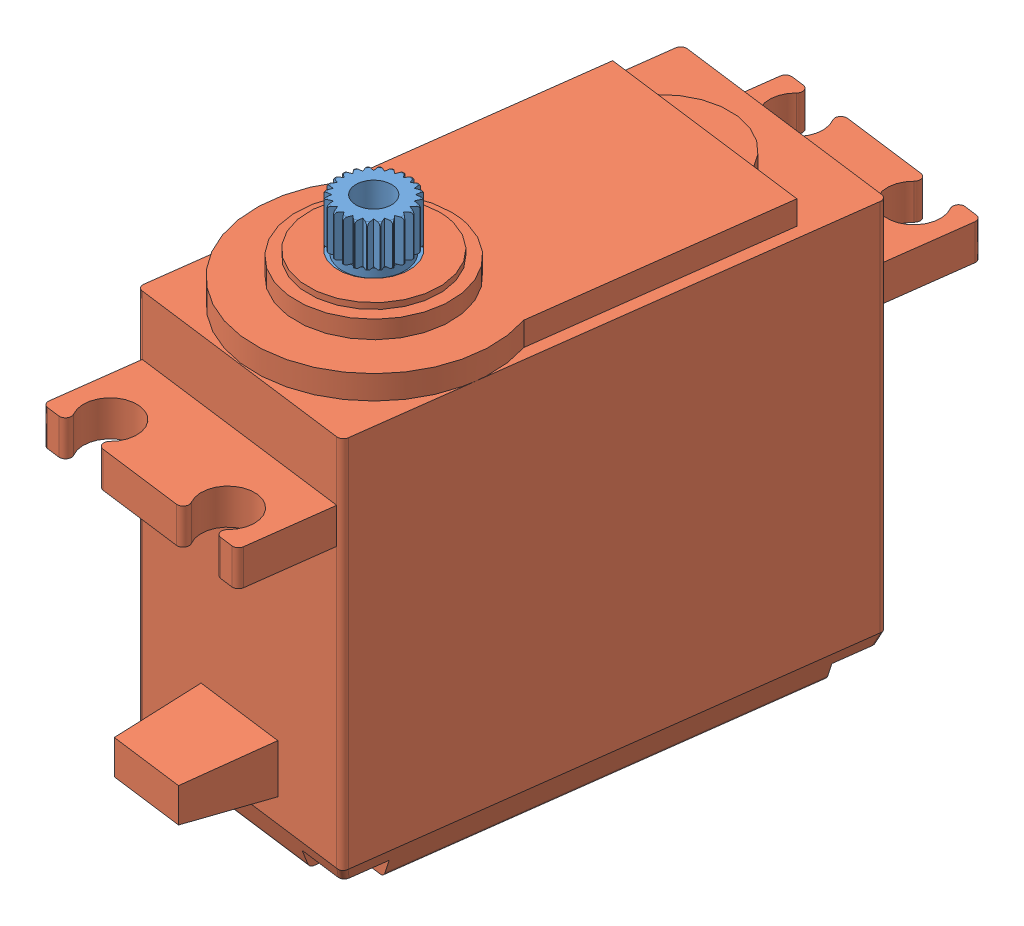
SolidWorks assembly Parallax-ServoMotor, configuration Default. Lengths in mm.
Overall size (27.07 42.02 58.21).
2 component instances, 2 part files, 2 mates.
Components (placement in the parent):
- Parallax-Gear-1: Parallax-Gear [Default] at (38.0124 26.9941 70.9424) size (6 6.02 6)
- Parallax-ServoMotor-1: Parallax-ServoMotor [Default] at (59.1176 62.726 61.92) x (-0.991636 0 -0.129064) z (0.129064 0 -0.991636) size (20 38 56.1)
Mates (geometry in assembly coordinates):
- Concentric1: concentric aligned: circle of Parallax-Gear-1; circle of Parallax-ServoMotor-1
- Coincident1: coincident anti-aligned: plane of Parallax-Gear-1 through (47.859 81.726 70.9424) normal (0 -1 0); plane of Parallax-ServoMotor-1 through (59.1176 81.726 61.92) normal (0 1 0)
